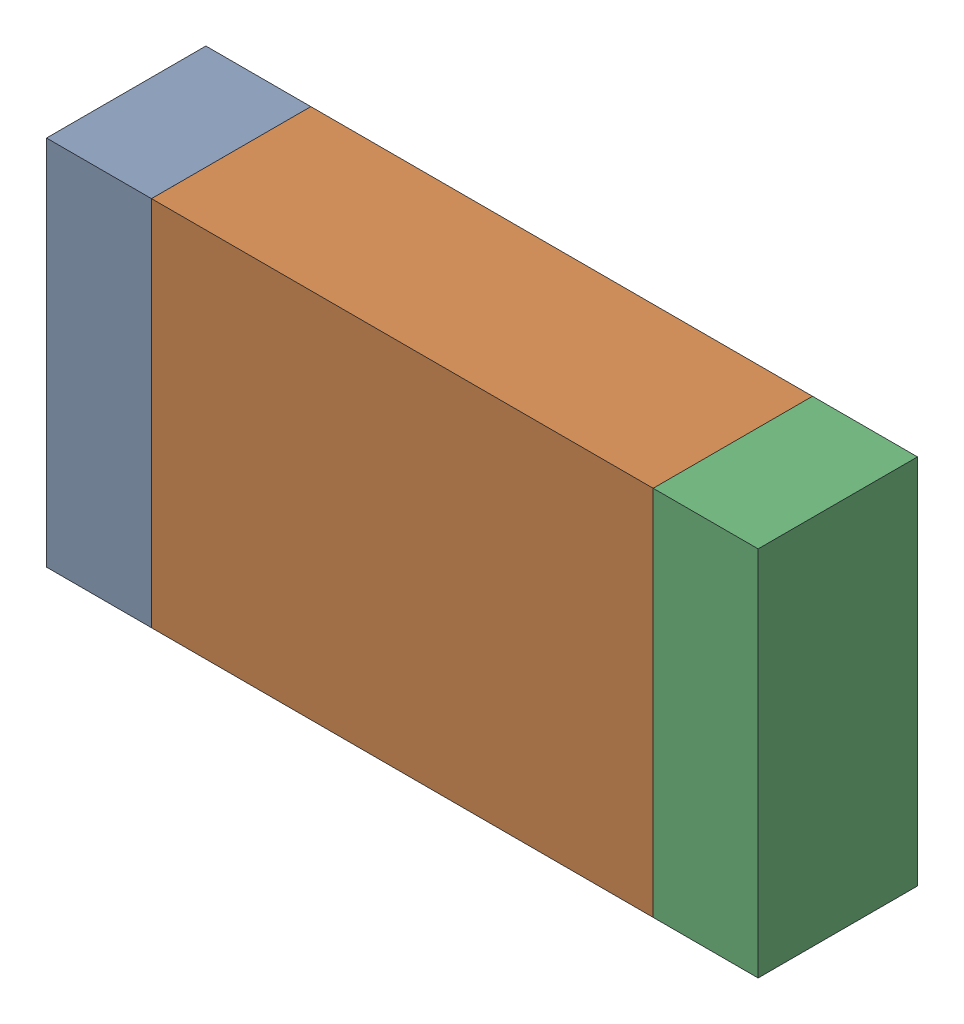
SolidWorks assembly R10, configuration Default. Lengths in mm.
Overall size (3.35 1.75 0.75).
6 component instances, 2 part files, 0 mates.
Components (placement in the parent):
- 959206760-1: 959206760 [Default] at (152.7506 83.5661 0) size (0.49 1.75 0.75)
  - Extruded-2-1: Extruded-2 [Default] at origin size (0.49 1.75 0.75)
- 959206896-1: 959206896 [Default] at (154.1781 83.5661 0) size (2.36 1.75 0.75)
  - Extruded-3-1: Extruded-3 [Default] at origin size (2.36 1.75 0.75)
- 959206760-2: 959206760 [Default] at (155.6056 83.5661 0) size (0.49 1.75 0.75)
  - Extruded-2-1: Extruded-2 [Default] at origin size (0.49 1.75 0.75)
